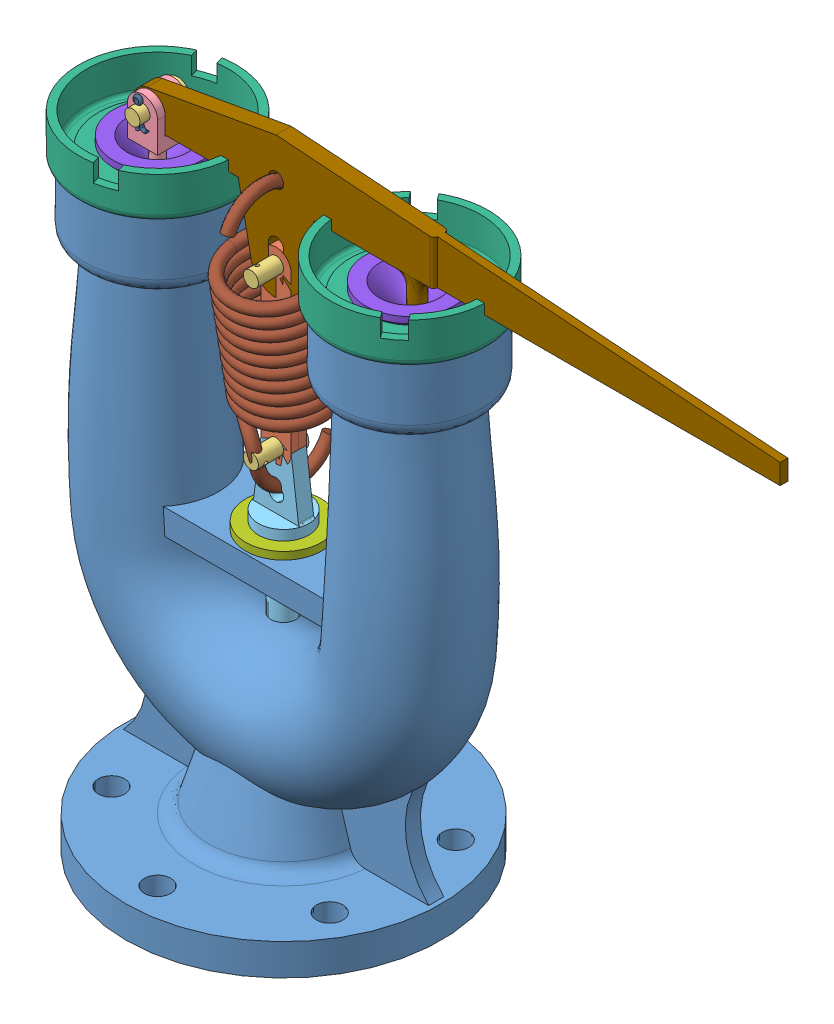
SolidWorks assembly rambottom spring assembly, configuration Default. Lengths in mm.
Overall size (575.17 494 250).
16 component instances, 11 part files, 41 mates.
Components (placement in the parent):
- body-2: body [Default] at (61.9158 -79.7114 412.9613) size (315 425 250)
- link-2: link [Default] at (61.9158 0.2886 415.8363) x (0 1 0) z (0 0 1) size (149 24 6.25)
- pin-2: pin [Default] at (-38.0842 183.2886 432.9613) x (-0.985134 -0.17179 0) z (0.17179 -0.985134 0) size (20 36 20)
- pivot-2: pivot [Default] at (-38.0842 183.2886 412.9613) x (-1 0 0) z (0 0 -1) size (24 58 24)
- shackle-2: shackle [Default] at (61.9158 -45.7114 412.9613) size (40 129 40)
- valve seat-2: valve seat [Default] at (-38.0842 103.2886 412.9613) x (-0.955776 0 0.294096) z (-0.294096 0 -0.955776) size (125 75 125)
- washer-2: washer [Default] at (61.9158 -59.7114 412.9613) size (60 6 60)
- valve seat-4: valve seat [Default] at (161.9158 103.2886 412.9613) x (-0.796693 0 0.604384) z (-0.604384 0 -0.796693) size (125 75 125)
- valve-3: valve [Default] at (-38.0842 101.2886 412.9613) x (-0.774499 0 -0.632576) z (0.632576 0 -0.774499) size (70 60 70)
- valve-4: valve [Default] at (161.9158 101.2886 412.9613) x (-0.90203 0 -0.431673) z (0.431673 0 -0.90203) size (70 60 70)
- link-3: link [Default] at (61.9158 0.2886 410.0863) x (0 1 0) z (0 0 1) size (149 24 6.25)
- lever-5: lever [Default] at (61.9158 183.2886 412.9613) size (510.05 112 12.47)
- split pin-5: split pin [Default] at (-39.5595 191.7485 426.9613) x (0.17179 -0.985134 0) z (0 0 1) size (23.5 8.01 3)
- pin-7: pin [Default] at (61.9158 0.2886 438.9613) x (0.31123 0.950335 0) z (-0.950335 0.31123 0) size (20 36 20)
- pin-8: pin [Default] at (61.9158 125.2886 438.9613) x (-0.986057 -0.166408 0) z (0.166408 -0.986057 0) size (20 36 20)
- spring-9: spring [Default] at (61.9158 29.4143 409.1199) x (0 -0.159488 0.9872) z (-1 0 0) size (78 246.82 78)
Mates (geometry in assembly coordinates):
- Concentric3: concentric aligned: circle of body-2; circle of valve seat-2
- Coincident3: coincident anti-aligned: plane of body-2 through (-38.0842 145.2886 412.9613) normal (0 1 0); plane of valve seat-2 through (16.8729 145.2886 396.0507) normal (0 -1 0)
- Concentric5: concentric anti-aligned: circle of body-2; circle of valve seat-4
- Coincident5: coincident anti-aligned: plane of body-2 through (161.9158 145.2886 412.9613) normal (0 1 0); plane of valve seat-4 through (207.7257 145.2886 378.2092) normal (0 -1 0)
- Concentric8: concentric aligned: circle of valve seat-2; circle of valve-3
- Coincident6: coincident aligned: cone of valve seat-2 through (-38.0842 149.2886 412.9613) axis (0 -1 0); cone of valve-3 through (-38.0842 156.2886 412.9613) axis (0 -1 0)
- Concentric9: concentric aligned: circle of valve seat-4; circle of valve-4
- Concentric10: concentric aligned: circle of valve seat-4; circle of valve-4
- Coincident7: coincident aligned: cone of valve seat-4 through (161.9158 149.2886 412.9613) axis (0 -1 0); cone of valve-4 through (161.9158 156.2886 412.9613) axis (0 -1 0)
- Concentric11: concentric aligned: cylinder of pivot-2 through (-38.0842 137.2886 412.9613) axis (0 -1 0) radius 5; cone of valve-3 through (-38.0842 137.2886 412.9613) axis (0 -1 0)
- Coincident8: coincident: point of pivot-2; point of valve-3
- Coincident19: coincident aligned: plane of body-2 through (51.9158 -104.7114 402.9613) normal (0 0 1); plane of washer-2 through (51.9158 -53.7114 402.9613) normal (0 0 1)
- Coincident20: coincident aligned: plane of body-2 through (51.9158 -104.7114 422.9613) normal (1 0 0); plane of washer-2 through (51.9158 -53.7114 422.9613) normal (1 0 0)
- Coincident21: coincident anti-aligned: plane of body-2 through (-95.5852 -59.7114 444.9613) normal (0 1 0); plane of washer-2 through (61.9158 -59.7114 412.9613) normal (0 -1 0)
- Coincident22: coincident anti-aligned: plane of shackle-2 through (51.9158 -71.7114 402.9613) normal (-1 0 0); plane of washer-2 through (51.9158 -53.7114 422.9613) normal (1 0 0)
- Coincident25: coincident anti-aligned: plane of shackle-2 through (51.9158 -71.7114 422.9613) normal (0 0 1); plane of washer-2 through (51.9158 -53.7114 422.9613) normal (0 0 -1)
- Coincident26: coincident anti-aligned: line of shackle-2 through (71.9158 -53.7114 422.9613) axis (-1 0 0); line of washer-2 through (51.9158 -53.7114 422.9613) axis (1 0 0)
- Coincident27: coincident aligned: circle of link-2; circle of shackle-2
- Coincident28: coincident aligned: plane of link-2 through (61.9158 0.2886 418.9613) normal (0 0 1); plane of shackle-2 through (61.9158 0.2886 418.9613) normal (0 0 1)
- Coincident29: coincident aligned: circle of shackle-2; circle of link-3
- Coincident30: coincident aligned: plane of shackle-2 through (61.9158 0.2886 406.9613) normal (0 0 -1); plane of link-3 through (61.9158 0.2886 406.9613) normal (0 0 -1)
- Concentric14: concentric anti-aligned: cylinder of pivot-2 through (-38.0842 183.2886 400.9613) axis (0 0 1) radius 6; cylinder of lever-5 through (-38.0842 183.2886 418.9613) axis (0 0 -1) radius 6
- Coincident31: coincident anti-aligned: plane of pivot-2 through (-26.0842 195.2886 418.9613) normal (0 0 -1); plane of lever-5 through (61.9158 183.2886 418.9613) normal (0 0 1)
- Parallel4: parallel aligned: cone of valve-4 through (161.9158 137.2886 412.9613) axis (0 -1 0); cone of lever-5 through (167.9158 147.6809 412.9613) axis (0 -1 0)
- Slot3: slot aligned: cylinder of link-2 through (61.9158 125.2886 418.9613) axis (0 0 -1) radius 6; cylinder of lever-5 through (61.9158 138.2886 418.9613) axis (0 0 -1) radius 6; cylinder of lever-5 through (61.9158 122.2886 418.9613) axis (0 0 -1) radius 6
- Slot4: slot aligned: cylinder of link-2 through (61.9158 125.2886 418.9613) axis (0 0 -1) radius 6; cylinder of lever-5 through (61.9158 138.2886 418.9613) axis (0 0 -1) radius 6; cylinder of lever-5 through (61.9158 122.2886 418.9613) axis (0 0 -1) radius 6
- Slot5: slot aligned: cylinder of link-3 through (61.9158 125.2886 413.2113) axis (0 0 -1) radius 6; cylinder of lever-5 through (61.9158 138.2886 418.9613) axis (0 0 -1) radius 6; cylinder of lever-5 through (61.9158 122.2886 418.9613) axis (0 0 -1) radius 6
- Concentric16: concentric aligned: cylinder of pin-2 through (-38.0842 183.2886 396.9613) axis (0 0 -1) radius 6; cylinder of lever-5 through (-38.0842 183.2886 418.9613) axis (0 0 -1) radius 6
- Coincident32: coincident anti-aligned: plane of pin-2 through (-43.995 182.2579 400.9613) normal (0 0 1); plane of pivot-2 through (-38.0842 183.2886 400.9613) normal (0 0 -1)
- Concentric22: concentric aligned: cylinder of pin-2 through (-39.2867 190.1846 426.9613) axis (0.17179 -0.985134 0) radius 1.5; cylinder of split pin-5 through (-38.9644 188.3359 426.9613) axis (0.17179 -0.985134 0) radius 1.5
- Tangent6: tangent anti-aligned: cylinder of pin-2 through (-38.0842 183.2886 396.9613) axis (0 0 -1) radius 6; torus of split pin-5
- Perpendicular1: perpendicular: plane of pivot-2 through (-38.0842 183.2886 424.9613) normal (0 0 1); line of split pin-5 through (-38.2768 190.214 428.4613) axis (0 0 -1)
- Concentric30: concentric aligned: cylinder of link-3 through (61.9158 125.2886 413.2113) axis (0 0 -1) radius 6; cylinder of pin-8 through (61.9158 125.2886 402.9613) axis (0 0 -1) radius 6
- Coincident40: coincident anti-aligned: plane of lever-5 through (61.9158 183.2886 406.9613) normal (0 0 -1); plane of pin-8 through (55.9995 124.2902 406.9613) normal (0 0 1)
- Concentric31: concentric aligned: cylinder of shackle-2 through (61.9158 0.2886 418.9613) axis (0 0 -1) radius 6; cylinder of pin-7 through (61.9158 0.2886 402.9613) axis (0 0 -1) radius 6
- Coincident41: coincident anti-aligned: plane of shackle-2 through (61.9158 0.2886 406.9613) normal (0 0 -1); plane of pin-7 through (63.7832 5.9906 406.9613) normal (0 0 1)
- Coincident48: coincident anti-aligned: plane of body-2 through (61.9158 -79.7114 412.9613) normal (1 0 0); plane of spring-9 through (61.9158 29.4143 409.1199) normal (-1 0 0)
- Tangent16: tangent aligned: cylinder of lever-5 through (61.9158 183.2886 418.9613) axis (0 0 -1) radius 6; torus of spring-9
- Tangent20: tangent aligned: cylinder of shackle-2 through (61.9158 -31.7114 418.9613) axis (0 0 -1) radius 6; face of spring-9
- Lock2: lock: unknown of lever-5; unknown of spring-9
- Lock3: lock: unknown of shackle-2; unknown of spring-9
